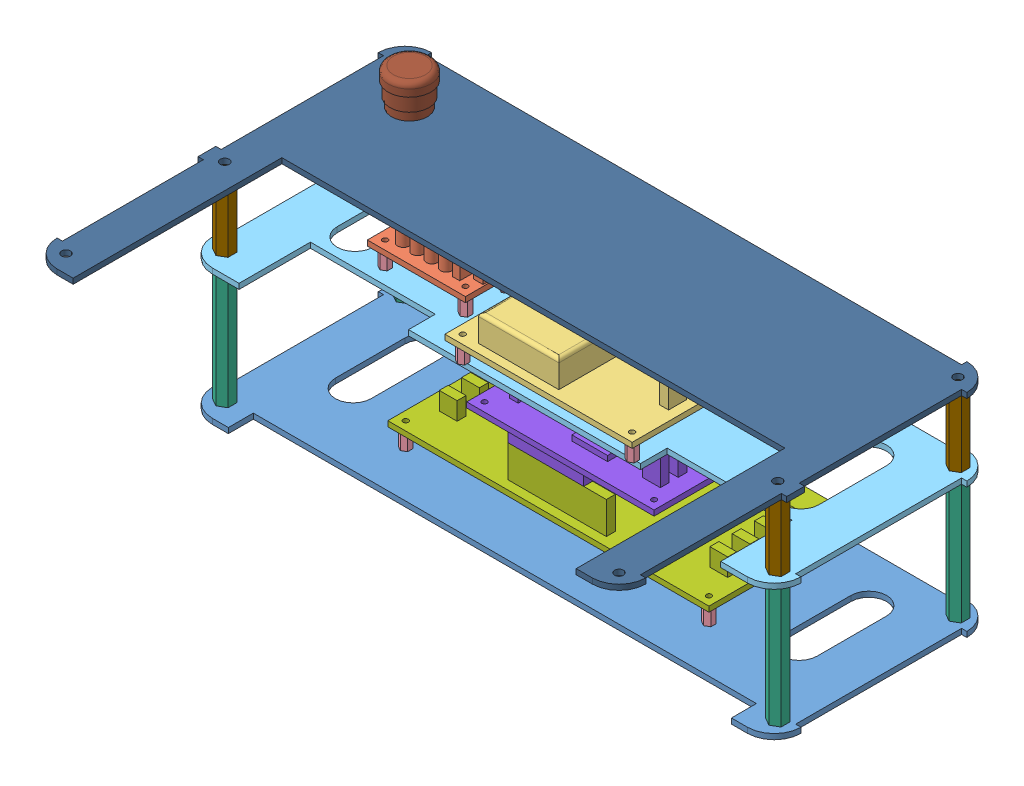
SolidWorks assembly plaque_electronique_1, configuration Default. Lengths in mm.
Overall size (330 139 210).
33 component instances, 11 part files, 67 mates.
Components (placement in the parent):
- plaque_plastique_L330_l123_decoupe-1: plaque_plastique_L330_l123_decoupe [Défaut] at (-146.0053 45.2677 19.7035) size (330 3 123)
- carte_hacheur-1: carte_hacheur [Default] at (-88.0975 131.2677 -67.2965) size (55 26 33)
- carte_hacheur-2: carte_hacheur [Default] at (-88.0975 131.2677 -24.2965) size (55 26 33)
- carte_puissance-1: carte_puissance [Default] at (-20.635 131.2677 -0.2965) size (105 23 100)
- entretoise_M3_L10-1: entretoise_M3_L10 [Default] at (-83.0975 121.2677 -72.2965) size (5.2 10 6)
- entretoise_M3_L10-2: entretoise_M3_L10 [Default] at (-38.0975 121.2677 -52.2965) size (5.2 10 6)
- entretoise_M3_L10-3: entretoise_M3_L10 [Default] at (-83.0975 121.2677 -29.2965) size (5.2 10 6)
- entretoise_M3_L10-4: entretoise_M3_L10 [Default] at (-15.635 121.2677 -95.2965) size (5.2 10 6)
- entretoise_M3_L10-5: entretoise_M3_L10 [Default] at (-83.0975 121.2677 -52.2965) size (5.2 10 6)
- entretoise_M3_L10-6: entretoise_M3_L10 [Default] at (-83.0975 121.2677 -95.2965) size (5.2 10 6)
- entretoise_M3_L10-7: entretoise_M3_L10 [Default] at (-38.0975 121.2677 -29.2965) size (5.2 10 6)
- entretoise_M3_L10-8: entretoise_M3_L10 [Default] at (79.365 121.2677 -5.2965) size (5.2 10 6)
- entretoise_M3_L10-9: entretoise_M3_L10 [Default] at (-15.635 121.2677 -5.2965) size (5.2 10 6)
- entretoise_M3_L10-10: entretoise_M3_L10 [Default] at (79.365 121.2677 -95.2965) size (5.2 10 6)
- entretoise_M3_L10-11: entretoise_M3_L10 [Default] at (-38.0975 121.2677 -72.2965) size (5.2 10 6)
- entretoise_M3_L10-12: entretoise_M3_L10 [Default] at (-38.0975 121.2677 -95.2965) size (5.2 10 6)
- plaque_plastique_L330_l123_decoupe_servos-3: plaque_plastique_L330_l123_decoupe_servos [Défaut] at (-146.0053 118.2677 19.7035) size (330 3 123)
- entretoise_M5_L70-7: entretoise_M5_L70 [Default] at (-136.0053 48.2677 7.7035) size (8.66 70 10)
- entretoise_M5_L70-6: entretoise_M5_L70 [Default] at (173.9947 48.2677 7.7035) size (8.66 70 10)
- entretoise_M5_L70-9: entretoise_M5_L70 [Default] at (-136.0053 48.2677 -93.2965) size (8.66 70 10)
- entretoise_M5_L70-8: entretoise_M5_L70 [Default] at (173.9947 48.2677 -93.2965) size (8.66 70 10)
- carte_interface_2-1: carte_interface_2 [Default] at (112.3847 58.2677 -100.2965) x (-1 0 0) z (0 0 -1) size (180 21 85)
- carte_PIC32_FPGA-1: carte_PIC32_FPGA [Default] at (79.3542 87.2677 -97.5564) x (-1 0 0) z (0 0 -1) size (115 36 80)
- entretoise_M3_L10-13: entretoise_M3_L10 [Default] at (107.3847 48.2677 -95.2965) size (5.2 10 6)
- entretoise_M3_L10-14: entretoise_M3_L10 [Default] at (-62.6153 48.2677 -95.2965) size (5.2 10 6)
- entretoise_M3_L10-15: entretoise_M3_L10 [Default] at (-62.6153 48.2677 -20.2965) size (5.2 10 6)
- entretoise_M3_L10-16: entretoise_M3_L10 [Default] at (107.3847 48.2677 -20.2965) size (5.2 10 6)
- entretoise_M5_L40-6: entretoise_M5_L40 [Default] at (-136.0053 121.2677 7.7035) size (8.66 40 10)
- entretoise_M5_L40-5: entretoise_M5_L40 [Default] at (-136.0053 121.2677 -93.2965) size (8.66 40 10)
- entretoise_M5_L40-3: entretoise_M5_L40 [Default] at (173.9947 121.2677 7.7035) size (8.66 40 10)
- entretoise_M5_L40-4: entretoise_M5_L40 [Default] at (173.9947 121.2677 -93.2965) size (8.66 40 10)
- plaque_plastique_L330_l210_decoupe_dessus-1: plaque_plastique_L330_l210_decoupe_dessus [Défaut] at (-146.0053 161.2677 106.7035) size (330 3 210)
- arret_urgence-1: arret_urgence [Default] at (-111.0053 177.2677 -70.8411) x (0.976487 0 -0.215576) z (0.215576 0 0.976487) size (24 42 24)
Mates (geometry in assembly coordinates):
- Coïncidente1: coincident anti-aligned: plane of carte_hacheur-1 through (-88.0975 131.2677 -100.2965) normal (0 -1 0); plane of entretoise_M3_L10-1 through (-83.0975 131.2677 -75.2965) normal (0 1 0)
- Coïncidente2: coincident anti-aligned: plane of carte_hacheur-1 through (-88.0975 131.2677 -100.2965) normal (0 -1 0); plane of entretoise_M3_L10-6 through (-83.0975 131.2677 -98.2965) normal (0 1 0)
- Coïncidente3: coincident anti-aligned: plane of carte_hacheur-1 through (-88.0975 131.2677 -100.2965) normal (0 -1 0); plane of entretoise_M3_L10-11 through (-38.0975 131.2677 -75.2965) normal (0 1 0)
- Coïncidente4: coincident anti-aligned: plane of carte_hacheur-1 through (-88.0975 131.2677 -100.2965) normal (0 -1 0); plane of entretoise_M3_L10-12 through (-38.0975 131.2677 -98.2965) normal (0 1 0)
- Coaxiale1: concentric aligned: cylinder of carte_hacheur-1; cylinder of entretoise_M3_L10-1
- Coaxiale2: concentric aligned: cylinder of carte_hacheur-1; cylinder of entretoise_M3_L10-6
- Coaxiale3: concentric aligned: cylinder of carte_hacheur-1; cylinder of entretoise_M3_L10-11
- Coaxiale4: concentric aligned: cylinder of carte_hacheur-1; cylinder of entretoise_M3_L10-12
- Coïncidente5: coincident anti-aligned: plane of carte_hacheur-2 through (-88.0975 131.2677 -57.2965) normal (0 -1 0); plane of entretoise_M3_L10-2 through (-38.0975 131.2677 -55.2965) normal (0 1 0)
- Coïncidente6: coincident anti-aligned: plane of carte_hacheur-2 through (-88.0975 131.2677 -57.2965) normal (0 -1 0); plane of entretoise_M3_L10-7 through (-38.0975 131.2677 -32.2965) normal (0 1 0)
- Coïncidente7: coincident anti-aligned: plane of carte_hacheur-2 through (-88.0975 131.2677 -57.2965) normal (0 -1 0); plane of entretoise_M3_L10-3 through (-83.0975 131.2677 -32.2965) normal (0 1 0)
- Coïncidente8: coincident anti-aligned: plane of carte_hacheur-2 through (-88.0975 131.2677 -57.2965) normal (0 -1 0); plane of entretoise_M3_L10-5 through (-83.0975 131.2677 -55.2965) normal (0 1 0)
- Coaxiale5: concentric aligned: cylinder of carte_hacheur-2; cylinder of entretoise_M3_L10-3
- Coaxiale6: concentric aligned: cylinder of carte_hacheur-2; cylinder of entretoise_M3_L10-5
- Coaxiale7: concentric aligned: cylinder of carte_hacheur-2; cylinder of entretoise_M3_L10-2
- Coaxiale8: concentric aligned: cylinder of carte_hacheur-2; cylinder of entretoise_M3_L10-7
- Coïncidente9: coincident anti-aligned: plane of carte_puissance-1 through (-20.635 131.2677 -100.2965) normal (0 -1 0); plane of entretoise_M3_L10-4 through (-15.635 131.2677 -98.2965) normal (0 1 0)
- Coïncidente10: coincident anti-aligned: plane of carte_puissance-1 through (-20.635 131.2677 -100.2965) normal (0 -1 0); plane of entretoise_M3_L10-8 through (79.365 131.2677 -8.2965) normal (0 1 0)
- Coïncidente11: coincident anti-aligned: plane of carte_puissance-1 through (-20.635 131.2677 -100.2965) normal (0 -1 0); plane of entretoise_M3_L10-10 through (79.365 131.2677 -98.2965) normal (0 1 0)
- Coïncidente12: coincident anti-aligned: plane of carte_puissance-1 through (-20.635 131.2677 -100.2965) normal (0 -1 0); plane of entretoise_M3_L10-9 through (-15.635 131.2677 -8.2965) normal (0 1 0)
- Coaxiale9: concentric aligned: cylinder of carte_puissance-1; cylinder of entretoise_M3_L10-9
- Coaxiale10: concentric aligned: cylinder of carte_puissance-1; cylinder of entretoise_M3_L10-4
- Coaxiale11: concentric aligned: cylinder of carte_puissance-1; cylinder of entretoise_M3_L10-8
- Coaxiale12: concentric aligned: cylinder of carte_puissance-1; cylinder of entretoise_M3_L10-10
- Coïncidente17: coincident aligned: plane of carte_hacheur-1 through (-88.0975 134.2677 -100.2965) normal (0 0 -1); plane of carte_puissance-1 through (-20.635 134.2677 -100.2965) normal (0 0 -1)
- Distance2: distance = 10 mm anti-aligned: plane of carte_hacheur-2 through (-88.0975 134.2677 -57.2965) normal (0 0 -1); plane of carte_hacheur-1 through (-88.0975 134.2677 -67.2965) normal (0 0 1)
- Coïncidente19: coincident aligned: plane of carte_hacheur-1 through (-33.0975 134.2677 -67.2965) normal (1 0 0); plane of carte_hacheur-2 through (-33.0975 134.2677 -24.2965) normal (1 0 0)
- Coïncidente20: coincident anti-aligned: plane of plaque_plastique_L330_l123_decoupe-1 through (-146.0053 48.2677 -103.2965) normal (0 1 0); plane of entretoise_M5_L70-7 through (-136.0053 48.2677 2.7035) normal (0 -1 0)
- Coïncidente21: coincident anti-aligned: plane of plaque_plastique_L330_l123_decoupe-1 through (-146.0053 48.2677 -103.2965) normal (0 1 0); plane of entretoise_M5_L70-9 through (-136.0053 48.2677 -98.2965) normal (0 -1 0)
- Coïncidente22: coincident anti-aligned: plane of plaque_plastique_L330_l123_decoupe-1 through (-146.0053 48.2677 -103.2965) normal (0 1 0); plane of entretoise_M5_L70-6 through (173.9947 48.2677 2.7035) normal (0 -1 0)
- Coïncidente23: coincident anti-aligned: plane of plaque_plastique_L330_l123_decoupe-1 through (-146.0053 48.2677 -103.2965) normal (0 1 0); plane of entretoise_M5_L70-8 through (173.9947 48.2677 -98.2965) normal (0 -1 0)
- Coaxiale14: concentric aligned: cylinder of plaque_plastique_L330_l123_decoupe-1; cylinder of entretoise_M5_L70-9
- Coaxiale15: concentric aligned: cylinder of plaque_plastique_L330_l123_decoupe-1; cylinder of entretoise_M5_L70-7
- Coaxiale16: concentric aligned: cylinder of plaque_plastique_L330_l123_decoupe-1; cylinder of entretoise_M5_L70-6
- Coaxiale17: concentric aligned: cylinder of plaque_plastique_L330_l123_decoupe-1; cylinder of entretoise_M5_L70-8
- Coaxiale18: concentric aligned: cylinder of plaque_plastique_L330_l123_decoupe_servos-3; cylinder of entretoise_M5_L70-9
- Coïncidente24: coincident anti-aligned: plane of plaque_plastique_L330_l123_decoupe_servos-3 through (-146.0053 118.2677 -103.2965) normal (0 -1 0); plane of entretoise_M5_L70-9 through (-136.0053 118.2677 -98.2965) normal (0 1 0)
- Coaxiale19: concentric aligned: cylinder of plaque_plastique_L330_l123_decoupe_servos-3; cylinder of entretoise_M5_L70-7
- Distance3: distance = 10 mm anti-aligned: plane of carte_interface_2-1 through (49.8847 79.2677 -95.2965) normal (0 1 0); plane of carte_PIC32_FPGA-1 through (37.1702 69.2677 -90.2965) normal (0 -1 0)
- Coïncidente26: coincident aligned: plane of carte_interface_2-1 through (49.8847 79.2677 -95.2965) normal (0 0 -1); plane of carte_PIC32_FPGA-1 through (37.1702 69.2677 -95.2965) normal (0 0 -1)
- Coïncidente27: coincident aligned: plane of carte_interface_2-1 through (-5.1153 79.2677 -90.2965) normal (-1 0 0); plane of carte_PIC32_FPGA-1 through (-5.1153 69.2677 -95.2965) normal (-1 0 0)
- Coïncidente28: coincident anti-aligned: plane of carte_interface_2-1 through (112.3847 58.2677 -15.2965) normal (0 -1 0); plane of entretoise_M3_L10-13 through (107.3847 58.2677 -98.2965) normal (0 1 0)
- Coïncidente29: coincident anti-aligned: plane of carte_interface_2-1 through (112.3847 58.2677 -15.2965) normal (0 -1 0); plane of entretoise_M3_L10-14 through (-62.6153 58.2677 -98.2965) normal (0 1 0)
- Coïncidente30: coincident anti-aligned: plane of carte_interface_2-1 through (112.3847 58.2677 -15.2965) normal (0 -1 0); plane of entretoise_M3_L10-16 through (107.3847 58.2677 -23.2965) normal (0 1 0)
- Coïncidente31: coincident anti-aligned: plane of carte_interface_2-1 through (112.3847 58.2677 -15.2965) normal (0 -1 0); plane of entretoise_M3_L10-15 through (-62.6153 58.2677 -23.2965) normal (0 1 0)
- Coaxiale20: concentric aligned: cylinder of carte_interface_2-1; cylinder of entretoise_M3_L10-15
- Coaxiale21: concentric aligned: cylinder of carte_interface_2-1; cylinder of entretoise_M3_L10-16
- Coaxiale22: concentric aligned: cylinder of carte_interface_2-1; cylinder of entretoise_M3_L10-14
- Coaxiale23: concentric aligned: cylinder of carte_interface_2-1; cylinder of entretoise_M3_L10-13
- Coïncidente34: coincident anti-aligned: plane of plaque_plastique_L330_l123_decoupe_servos-3 through (-146.0053 121.2677 -103.2965) normal (0 1 0); plane of entretoise_M5_L40-6 through (-136.0053 121.2677 2.7035) normal (0 -1 0)
- Coïncidente35: coincident anti-aligned: plane of plaque_plastique_L330_l123_decoupe_servos-3 through (-146.0053 121.2677 -103.2965) normal (0 1 0); plane of entretoise_M5_L40-5 through (-136.0053 121.2677 -98.2965) normal (0 -1 0)
- Coïncidente36: coincident anti-aligned: plane of plaque_plastique_L330_l123_decoupe_servos-3 through (-146.0053 121.2677 -103.2965) normal (0 1 0); plane of entretoise_M5_L40-3 through (173.9947 121.2677 2.7035) normal (0 -1 0)
- Coïncidente37: coincident anti-aligned: plane of plaque_plastique_L330_l123_decoupe_servos-3 through (-146.0053 121.2677 -103.2965) normal (0 1 0); plane of entretoise_M5_L40-4 through (173.9947 121.2677 -98.2965) normal (0 -1 0)
- Coaxiale24: concentric aligned: cylinder of plaque_plastique_L330_l123_decoupe_servos-3; cylinder of entretoise_M5_L40-4
- Coaxiale25: concentric aligned: cylinder of plaque_plastique_L330_l123_decoupe_servos-3; cylinder of entretoise_M5_L40-3
- Coaxiale26: concentric aligned: cylinder of plaque_plastique_L330_l123_decoupe_servos-3; cylinder of entretoise_M5_L40-5
- Coaxiale27: concentric aligned: cylinder of plaque_plastique_L330_l123_decoupe_servos-3; cylinder of entretoise_M5_L40-6
- Coïncidente38: coincident anti-aligned: plane of entretoise_M5_L40-5 through (-136.0053 161.2677 -98.2965) normal (0 1 0); plane of plaque_plastique_L330_l210_decoupe_dessus-1 through (-146.0053 161.2677 -103.2965) normal (0 -1 0)
- Coaxiale28: concentric aligned: cylinder of entretoise_M5_L40-5; cylinder of plaque_plastique_L330_l210_decoupe_dessus-1
- Coaxiale29: concentric anti-aligned: cylinder of plaque_plastique_L330_l210_decoupe_dessus-1; cylinder of arret_urgence-1
- Coïncidente40: coincident anti-aligned: plane of plaque_plastique_L330_l210_decoupe_dessus-1 through (-146.0053 164.2677 -103.2965) normal (0 1 0); plane of arret_urgence-1 through (-111.0053 164.2677 -70.8411) normal (0 -1 0)
- Coïncidente41: coincident aligned: plane of carte_puissance-1 through (-20.635 134.2677 -100.2965) normal (0 0 -1); plane of carte_interface_2-1 through (112.3847 61.2677 -100.2965) normal (0 0 -1)
- Coïncidente42: coincident aligned: plane of plaque_plastique_L330_l123_decoupe-1 through (-131.0053 45.2667 -100.2965) normal (0 0 -1); plane of carte_puissance-1 through (-20.635 134.2677 -100.2965) normal (0 0 -1)
- Coïncidente43: coincident anti-aligned: plane of plaque_plastique_L330_l123_decoupe-1 through (-146.0053 48.2677 -103.2965) normal (0 1 0); plane of entretoise_M3_L10-14 through (-62.6153 48.2677 -98.2965) normal (0 -1 0)
- Coïncidente44: coincident anti-aligned: plane of entretoise_M3_L10-5 through (-83.0975 121.2677 -55.2965) normal (0 -1 0); plane of plaque_plastique_L330_l123_decoupe_servos-3 through (-146.0053 121.2677 -103.2965) normal (0 1 0)
- Coïncidente45: coincident aligned: plane of carte_hacheur-1 through (-88.0975 134.2677 -100.2965) normal (0 1 0); plane of carte_hacheur-2 through (-88.0975 134.2677 -57.2965) normal (0 1 0)
- Coïncidente46: coincident anti-aligned: plane of entretoise_M3_L10-10 through (79.365 121.2677 -98.2965) normal (0 -1 0); plane of plaque_plastique_L330_l123_decoupe_servos-3 through (-146.0053 121.2677 -103.2965) normal (0 1 0)
